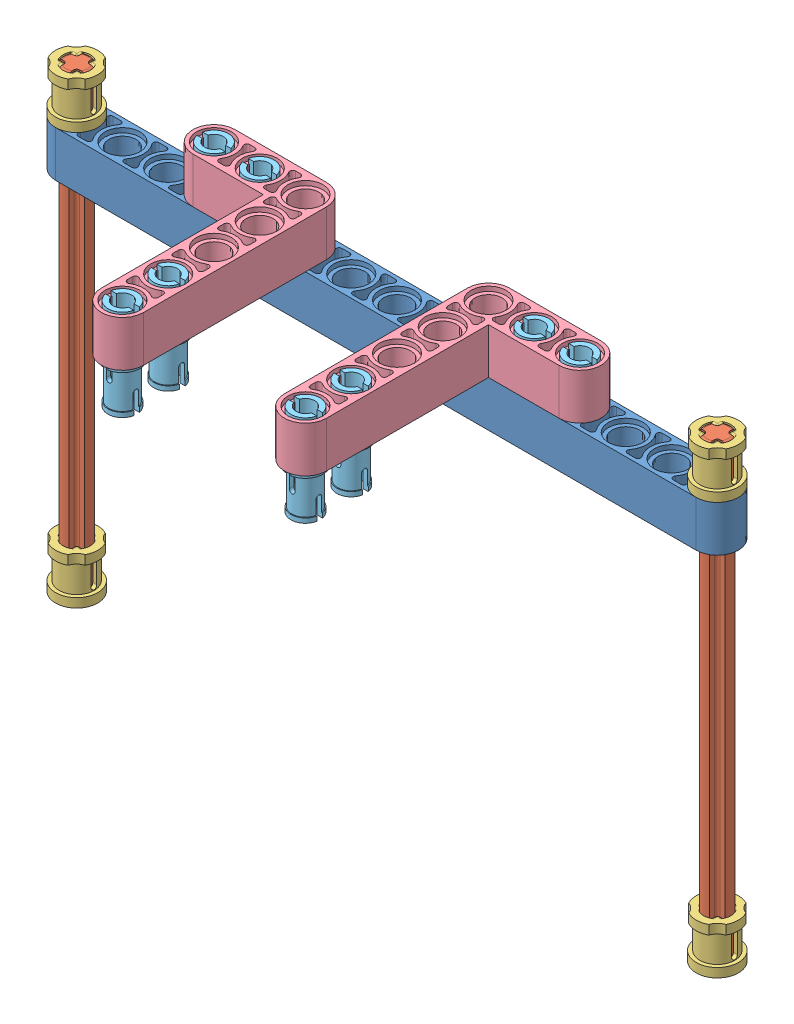
SolidWorks assembly NXT Mount, configuration Default. Lengths in mm.
Overall size (120.35 81.06 39.7).
17 component instances, 5 part files, 39 mates.
Components (placement in the parent):
- beam_15-1: beam_15 [Default] at (-56.455 -4.0325 0) size (120.35 8.06 7.44)
- axle_10-1: axle_10 [Default] at (56.455 12.0975 0) x (1 0 0) z (0 0 -1) size (4.78 80.73 4.78)
- axle_10-2: axle_10 [Default] at (-56.455 -68.5525 0) size (4.78 80.73 4.78)
- bushing-1: bushing [Default] at (-56.455 -60.4875 0) x (1 0 0) z (0 0 -1) size (7.44 8.48 7.44)
- bushing-2: bushing [Default] at (56.455 -60.4875 0) x (1 0 0) z (0 0 -1) size (7.44 8.48 7.44)
- bushing-3: bushing [Default] at (-56.455 12.0975 0) x (1 0 0) z (0 0 -1) size (7.44 8.48 7.44)
- bushing-4: bushing [Default] at (56.455 12.0975 0) x (1 0 0) z (0 0 -1) size (7.44 8.48 7.44)
- beam_angle_5x3-1: beam_angle_5x3 [Default] at (16.13 8.065 32.26) x (0 0 1) z (-1 0 0) size (39.7 8.07 23.57)
- conn-1: conn [Default] at (24.195 4.0325 0) x (1 0 0) z (0 0 -1) size (6.15 16.1 6.07)
- conn-2: conn [Default] at (16.13 4.0325 24.195) x (1 0 0) z (0 0 -1) size (6.15 16.1 6.07)
- conn-3: conn [Default] at (32.26 4.0325 0) x (1 0 0) z (0 0 -1) size (6.15 16.1 6.07)
- conn-5: conn [Default] at (16.13 4.0325 32.26) x (1 0 0) z (0 0 -1) size (6.15 16.1 6.07)
- beam_angle_5x3-2: beam_angle_5x3 [Default] at (-16.13 8.065 32.26) x (0 0 1) z (1 0 0) size (39.7 8.07 23.57)
- conn-4: conn [Default] at (-16.13 4.0325 32.26) size (6.15 16.1 6.07)
- conn-6: conn [Default] at (-32.26 4.0325 0) x (1 0 0) z (0 0 -1) size (6.15 16.1 6.07)
- conn-7: conn [Default] at (-24.195 4.0325 0) size (6.15 16.1 6.07)
- conn-8: conn [Default] at (-16.13 4.0325 24.195) size (6.15 16.1 6.07)
Mates (geometry in assembly coordinates):
- Concentric89: concentric aligned: cylinder of bushing-2 through (56.455 -60.4391 0) axis (0 -1 0) radius 2.39; cylinder of axle_10-1 through (56.455 11.5975 0) axis (0 -1 0) radius 2.39
- Concentric93: concentric aligned: cylinder of axle_10-1 through (56.455 11.5975 0) axis (0 -1 0) radius 2.39; cylinder of bushing-4 through (56.455 12.1459 0) axis (0 -1 0) radius 2.39
- Concentric90: concentric anti-aligned: cylinder of axle_10-2 through (-56.455 -68.0525 0) axis (0 1 0) radius 2.39; cylinder of bushing-1 through (-56.455 -60.4391 0) axis (0 -1 0) radius 2.39
- Concentric92: concentric anti-aligned: cylinder of bushing-3 through (-56.455 12.1459 0) axis (0 -1 0) radius 2.39; cylinder of axle_10-2 through (-56.455 -68.0525 0) axis (0 1 0) radius 2.39
- Coincident85: coincident anti-aligned: plane of beam_15-1 through (-62.582 4.0325 3.8688) normal (0 1 0); plane of bushing-3 through (-60.3238 4.0325 -3.872) normal (0 -1 0)
- Coincident86: coincident anti-aligned: plane of beam_15-1 through (-62.582 4.0325 3.8688) normal (0 1 0); plane of bushing-4 through (52.5862 4.0325 -3.872) normal (0 -1 0)
- Coincident88: coordinate: point of beam_15-1; point of assembly
- Concentric94: concentric: cylinder of beam_15-1 through (56.455 -3.2175 0) axis (0 1 0) radius 2.39; cylinder of axle_10-1 through (56.455 11.5975 0) axis (0 -1 0) radius 2.39
- Concentric96: concentric aligned: cylinder of beam_15-1 through (-56.455 -3.2175 0) axis (0 1 0) radius 2.39; cylinder of axle_10-2 through (-56.455 -68.0525 0) axis (0 1 0) radius 2.39
- Parallel1: parallel anti-aligned: plane of axle_10-1 through (56.455 12.0975 0) normal (0 0 -1); plane of assembly through (0 0 0) normal (0 0 1)
- Coincident90: coincident aligned: plane of axle_10-1 through (54.4679 12.0975 -1.9871) normal (0 1 0); plane of bushing-4 through (52.5834 12.0975 -3.8716) normal (0 1 0)
- Parallel2: parallel aligned: plane of axle_10-2 through (-56.455 -68.5525 0) normal (0 0 1); plane of assembly through (0 0 0) normal (0 0 1)
- Coincident92: coincident aligned: plane of axle_10-2 through (-58.4421 12.0975 1.9871) normal (0 1 0); plane of bushing-3 through (-60.3266 12.0975 -3.8716) normal (0 1 0)
- Parallel3: parallel anti-aligned: plane of bushing-1 through (-56.455 -60.4875 0) normal (0 0 -1); plane of assembly through (0 0 0) normal (0 0 1)
- Coincident94: coincident aligned: plane of axle_10-2 through (-58.4421 -68.5525 1.9871) normal (0 -1 0); plane of bushing-1 through (-60.3238 -68.5525 -3.872) normal (0 -1 0)
- Coincident95: coincident aligned: plane of axle_10-1 through (54.4679 -68.5525 -1.9871) normal (0 -1 0); plane of bushing-2 through (52.5862 -68.5525 -3.872) normal (0 -1 0)
- Parallel4: parallel anti-aligned: plane of bushing-2 through (56.455 -60.4875 0) normal (0 0 -1); plane of assembly through (0 0 0) normal (0 0 1)
- Parallel5: parallel anti-aligned: plane of bushing-3 through (-56.455 12.0975 0) normal (0 0 -1); plane of assembly through (0 0 0) normal (0 0 1)
- Parallel6: parallel anti-aligned: plane of bushing-4 through (56.455 12.0975 0) normal (0 0 -1); plane of assembly through (0 0 0) normal (0 0 1)
- Coincident100: coincident aligned: circle of beam_angle_5x3-2; circle of conn-4
- Coincident101: coincident aligned: circle of beam_angle_5x3-2; circle of conn-8
- Coincident103: coincident anti-aligned: circle of beam_angle_5x3-2; circle of conn-6
- Parallel7: parallel aligned: plane of beam_angle_5x3-2 through (-16.13 8.065 32.26) normal (1 0 0); plane of assembly through (0 0 0) normal (1 0 0)
- Parallel8: parallel aligned: plane of assembly through (0 0 0) normal (0 0 1); plane of conn-8 through (-16.13 4.0325 24.195) normal (0 0 1)
- Parallel9: parallel aligned: plane of assembly through (0 0 0) normal (0 0 1); plane of conn-7 through (-24.195 4.0325 0) normal (0 0 1)
- Parallel10: parallel anti-aligned: plane of assembly through (0 0 0) normal (0 0 1); plane of conn-6 through (-32.26 4.0325 0) normal (0 0 -1)
- Parallel11: parallel aligned: plane of assembly through (0 0 0) normal (0 0 1); plane of conn-4 through (-16.13 4.0325 32.26) normal (0 0 1)
- Parallel12: parallel anti-aligned: plane of assembly through (0 0 0) normal (0 0 1); plane of conn-5 through (16.13 4.0325 32.26) normal (0 0 -1)
- Parallel13: parallel anti-aligned: plane of assembly through (0 0 0) normal (0 0 1); plane of conn-3 through (32.26 4.0325 0) normal (0 0 -1)
- Parallel14: parallel anti-aligned: plane of assembly through (0 0 0) normal (0 0 1); plane of conn-2 through (16.13 4.0325 24.195) normal (0 0 -1)
- Parallel15: parallel anti-aligned: plane of assembly through (0 0 0) normal (0 0 1); plane of conn-1 through (24.195 4.0325 0) normal (0 0 -1)
- Parallel16: parallel anti-aligned: plane of beam_angle_5x3-1 through (16.13 8.065 32.26) normal (-1 0 0); plane of assembly through (0 0 0) normal (1 0 0)
- Coincident107: coincident anti-aligned: circle of beam_angle_5x3-1; circle of conn-5
- Coincident108: coincident anti-aligned: circle of beam_angle_5x3-1; circle of conn-2
- Coincident109: coincident anti-aligned: circle of beam_angle_5x3-1; circle of conn-3
- Coincident112: coincident anti-aligned: circle of beam_angle_5x3-1; circle of conn-1
- Coincident113: coincident aligned: circle of beam_angle_5x3-2; circle of conn-7
- Coincident115: coincident anti-aligned: circle of beam_15-1; circle of conn-7
- Coincident116: coincident aligned: circle of beam_15-1; circle of conn-1
